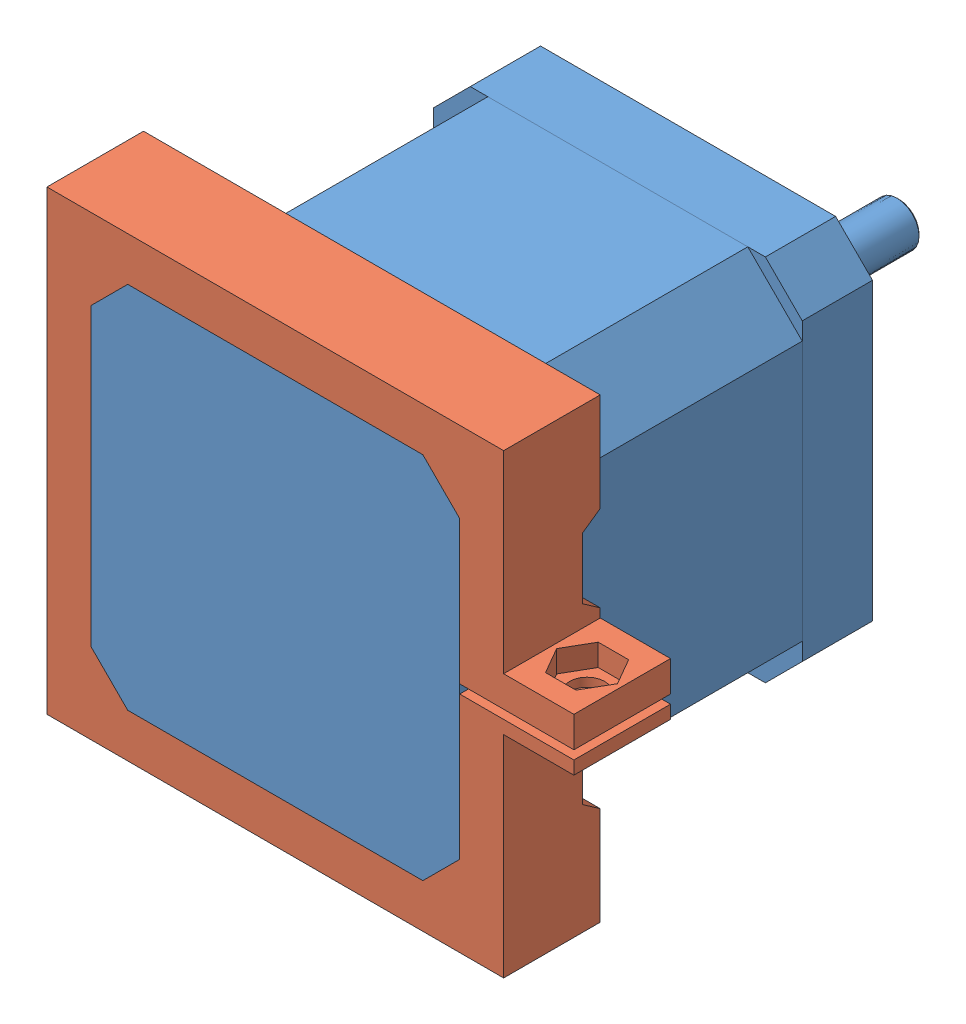
SolidWorks assembly Assemblage1, configuration Défaut. Lengths in mm.
Overall size (60 52 71).
2 component instances, 2 part files, 3 mates.
Components (placement in the parent):
- nema17-1: nema17 [Défaut] at origin size (42 42 71)
- x_nema17_attach-1: x_nema17_attach [Défaut] at (0 0 47) x (1 0 0) z (0 0 -1) size (60 52 11)
Mates (geometry in assembly coordinates):
- Coïncidente1: coincident: plane of nema17-1 through (0 0 38) normal (0 0 -1); plane of x_nema17_attach-1 through (-0.3173 -1.4062 38) normal (0 0 1)
- Coïncidente2: coincident: line of nema17-1 through (-21 4 45) axis (0 0 -1); line of x_nema17_attach-1 through (-21 4 45) axis (0 0 -1)
- Coïncidente3: coincident anti-aligned: line of nema17-1 through (21 -16.8 47) axis (0 1 0); line of x_nema17_attach-1 through (21 -0.5 47) axis (0 -1 0)
